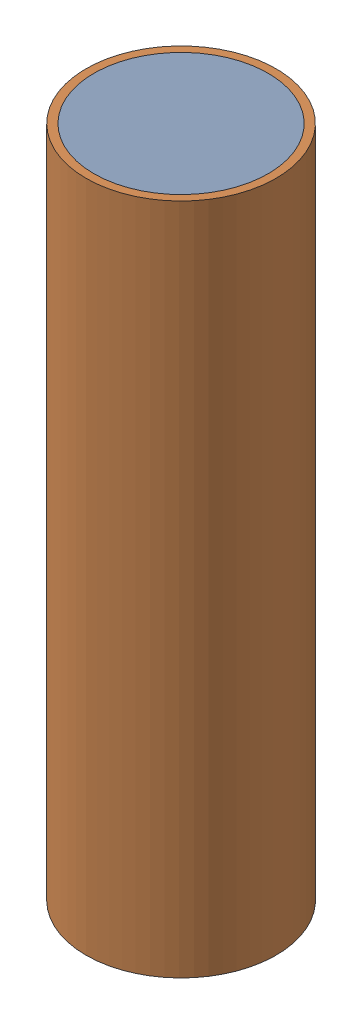
SolidWorks assembly fuel with shielding and channel, configuration Default. Lengths in mm.
Overall size (24 85 24).
2 component instances, 2 part files, 2 mates.
Components (placement in the parent):
- fuel-1: fuel [Default] at origin size (22 85 22)
- fuel shielding-1: fuel shielding [Default] at origin size (24 85 24)
Mates (geometry in assembly coordinates):
- Concentric1: concentric aligned: cylinder of fuel-1 through (0 85 0) axis (0 -1 0) radius 11; cylinder of fuel shielding-1 through (0 85 0) axis (0 -1 0) radius 11
- Coincident1: coincident aligned: plane of fuel-1 through (0 85 0) normal (0 1 0); plane of fuel shielding-1 through (0 85 0) normal (0 1 0)
